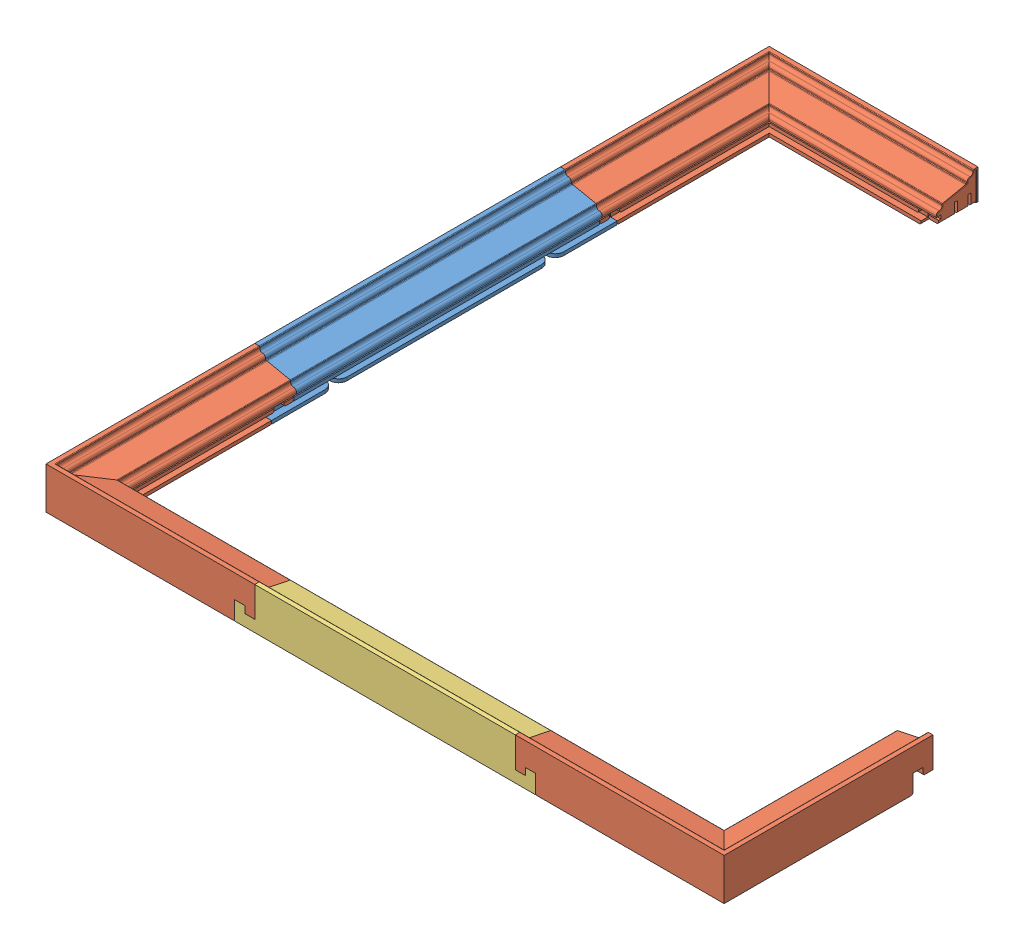
SolidWorks assembly new master, configuration Default. Lengths in mm.
Overall size (406 25 433).
5 component instances, 3 part files, 18 mates.
Components (placement in the parent):
- ccenter height big-1: ccenter height big [Default] at (-45.5621 -3.702 -38.5309) size (25 25 207)
- corner-1: corner [Default] at (-45.5621 -3.702 -151.5309) size (125 25 125)
- corner-2: corner [Default] at (-45.5621 -3.702 281.4691) x (0 0 -1) z (1 0 0) size (125 25 125)
- corner-3: corner [Default] at (360.4379 -3.702 281.4691) x (-1 0 0) z (0 0 -1) size (125 25 125)
- ccenter width big-1: ccenter width big [Default] at (67.4379 -3.702 281.4691) x (0 0 -1) z (1 0 0) size (25 25 180)
Mates (geometry in assembly coordinates):
- Coincident1: coincident aligned: plane of ccenter height big-1 through (-23.5621 7.398 168.4691) normal (0 -1 0); plane of corner-1 through (-23.5621 7.398 -26.5309) normal (0 -1 0)
- Coincident2: coincident aligned: plane of ccenter height big-1 through (-41.5621 -3.702 -38.5309) normal (1 0 0); plane of corner-1 through (-41.5621 9.798 -26.5309) normal (1 0 0)
- Coincident3: coincident anti-aligned: plane of ccenter height big-1 through (-20.5621 -3.702 -32.5309) normal (0 0 1); plane of corner-1 through (-20.5621 -3.702 -32.5309) normal (0 0 -1)
- Coincident4: coincident aligned: plane of ccenter height big-1 through (-23.5621 7.398 168.4691) normal (0 -1 0); plane of corner-2 through (79.4379 7.398 259.4691) normal (0 -1 0)
- Coincident5: coincident aligned: plane of ccenter height big-1 through (-41.5621 -3.702 -38.5309) normal (1 0 0); plane of corner-2 through (-41.5621 9.798 156.4691) normal (1 0 0)
- Coincident6: coincident anti-aligned: plane of ccenter height big-1 through (-20.5621 -3.702 162.4691) normal (0 0 -1); plane of corner-2 through (-20.5621 -3.702 162.4691) normal (0 0 1)
- Coincident7: coincident aligned: plane of corner-2 through (79.4379 7.398 259.4691) normal (0 -1 0); plane of ccenter height big-2 through (274.4379 7.398 259.4691) normal (0 -1 0)
- Coincident8: coincident aligned: plane of corner-2 through (79.4379 9.798 277.4691) normal (0 0 -1); plane of ccenter height big-2 through (67.4379 -3.702 277.4691) normal (0 0 -1)
- Coincident9: coincident anti-aligned: plane of corner-2 through (73.4379 -3.702 256.4691) normal (-1 0 0); plane of ccenter height big-2 through (73.4379 -3.702 256.4691) normal (1 0 0)
- Coincident10: coincident aligned: plane of ccenter height big-2 through (67.4379 -3.702 277.4691) normal (0 0 -1); plane of corner-3 through (262.4379 9.798 277.4691) normal (0 0 -1)
- Coincident11: coincident aligned: plane of ccenter height big-2 through (274.4379 7.398 259.4691) normal (0 -1 0); plane of corner-3 through (365.4379 7.398 156.4691) normal (0 -1 0)
- Coincident12: coincident anti-aligned: plane of ccenter height big-2 through (268.4379 -3.702 256.4691) normal (-1 0 0); plane of corner-3 through (268.4379 -3.702 256.4691) normal (1 0 0)
- Coincident14: coincident aligned: plane of corner-2 through (79.4379 9.798 277.4691) normal (0 0 -1); plane of ccenter width big-1 through (67.4379 -3.702 277.4691) normal (0 0 -1)
- Coincident15: coincident aligned: plane of corner-2 through (79.4379 7.398 259.4691) normal (0 -1 0); plane of ccenter width big-1 through (247.4379 7.398 259.4691) normal (0 -1 0)
- Coincident16: coincident anti-aligned: plane of corner-2 through (73.4379 -3.702 256.4691) normal (-1 0 0); plane of ccenter width big-1 through (73.4379 -3.702 256.4691) normal (1 0 0)
- Coincident17: coincident aligned: plane of corner-3 through (338.4379 7.398 156.4691) normal (0 -1 0); plane of ccenter width big-1 through (247.4379 7.398 259.4691) normal (0 -1 0)
- Coincident18: coincident aligned: plane of corner-3 through (235.4379 9.798 277.4691) normal (0 0 -1); plane of ccenter width big-1 through (67.4379 -3.702 277.4691) normal (0 0 -1)
- Coincident19: coincident anti-aligned: plane of corner-3 through (241.4379 -3.702 256.4691) normal (1 0 0); plane of ccenter width big-1 through (241.4379 -3.702 256.4691) normal (-1 0 0)
